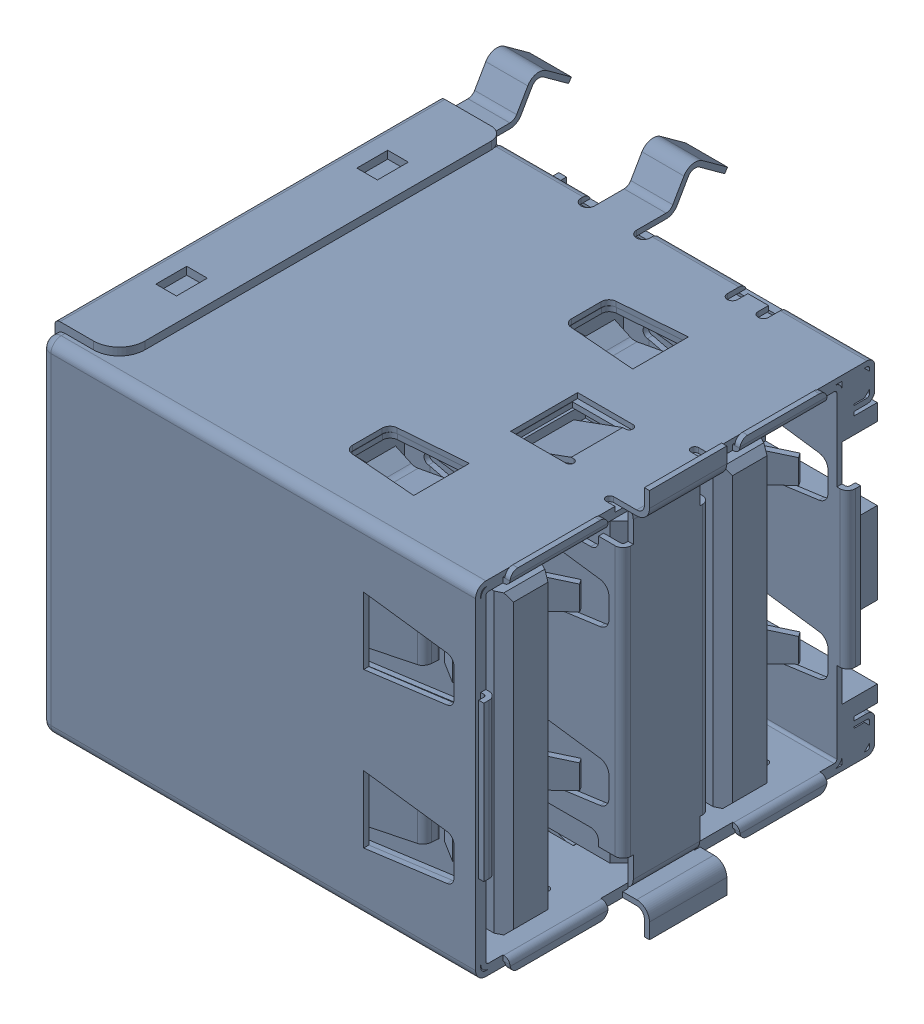
SolidWorks assembly USB_Ports_2,3_USB1, configuration Default. Lengths in mm.
Overall size (18 15.6 18.75).
2 component instances, 1 part files, 0 mates.
Components (placement in the parent):
- 672984090-1: 672984090 [Default] at (183.97 57.1499 8) x (0 1 0) z (1 0 0) size (15.6 18.75 18)
  - Open CASCADE STEP translator 6.2 1.82.1.1-1: Open CASCADE STEP translator 6.2 1.82.1.1 [Default] at origin size (15.6 18.75 18)
